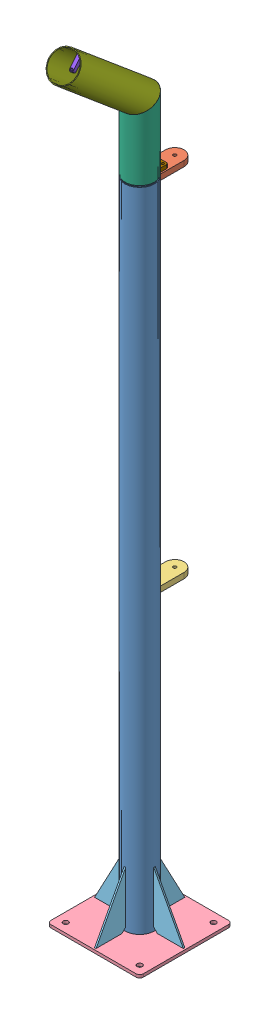
SolidWorks assembly FitLux_MecanoSoudure_Inox, configuration Default. Lengths in mm.
Overall size (250 2146.68 356.51).
14 component instances, 9 part files, 3 mates.
Components (placement in the parent):
- Ftx_Support-1: Ftx_Support [Défaut] at (-50.0643 -483.2351 108.1725) size (250 1758 250)
  - Tube_80x2x1750-1: Tube_80x2x1750 [Défaut] at (-29.6678 -485.0572 0) size (80 1750 80)
  - Ftx_BrideStatorSup-1: Ftx_BrideStatorSup [Défaut] at (-29.6678 1264.9428 0) x (-1 0 0) z (0 0 1) size (50 15 88.78)
  - Ftx_BrideStatorInf-1: Ftx_BrideStatorInf [Défaut] at (-29.6678 284.9428 0) size (50 15 88.78)
  - Ftx_Platine-1: Ftx_Platine [Défaut] at (-154.6678 -493.0572 125) size (250 8 250)
  - Ftx_Renfort-2: Ftx_Renfort [Défaut] at (-149.6678 -485.0572 0) size (80 150 4)
  - Ftx_Renfort-3: Ftx_Renfort [Défaut] at (-29.6678 -485.0572 120) x (0 0 -1) z (1 0 0) size (80 150 4)
  - Ftx_Renfort-4: Ftx_Renfort [Défaut] at (90.3322 -485.0572 0) x (-1 0 0) z (0 0 -1) size (80 150 4)
  - Ftx_Renfort-5: Ftx_Renfort [Défaut] at (-29.6678 -485.0572 -120) x (0 0 1) z (-1 0 0) size (80 150 4)
- Ftx_SupportEclairage-1: Ftx_SupportEclairage [Défaut] at (-79.7321 876.9485 65.011) x (0 0 -1) z (1 0 0) size (284.01 394.68 80)
  - Ftx_TubeEclairage_2-1: Ftx_TubeEclairage_2 [Défaut] at (-43.1615 -91.2409 0) size (80 210 80)
  - Ftx_TubeEclairage_1-1: Ftx_TubeEclairage_1 [Défaut] at (-248.9611 262.7932 0) x (0.642788 0.766044 0) z (0 0 -1) size (80 287.3 80)
  - Ftx_BrideEclairage-1: Ftx_BrideEclairage [Défaut] at (-219.8514 238.3672 0) x (-0.642788 -0.766044 0) z (0 0 -1) size (43 10 10)
  - Ftx_BrideSupportEclairage-1: Ftx_BrideSupportEclairage [Défaut] at (-43.1615 -91.2409 0) x (0 0 1) z (-1 0 0) size (50 10 21.28)
Mates (geometry in assembly coordinates):
- Coaxiale5: concentric aligned: cylinder of Ftx_Support-1/Ftx_BrideStatorSup-1 through (-62.2321 781.7076 63.1725) axis (0 1 0) radius 2.5; cylinder of Ftx_SupportEclairage-1/Ftx_BrideSupportEclairage-1 through (-62.2321 785.7076 63.1725) axis (0 1 0) radius 3.25
- Coaxiale6: concentric aligned: cylinder of Ftx_Support-1/Tube_80x2x1750-1 through (-79.7321 781.7076 108.1725) axis (0 -1 0) radius 38; cylinder of Ftx_SupportEclairage-1/Ftx_TubeEclairage_2-1 through (-79.7321 1085.7076 108.1725) axis (0 -1 0) radius 38
- Distance1: distance = 4 mm anti-aligned: plane of Ftx_SupportEclairage-1/Ftx_TubeEclairage_2-1 through (-79.7321 785.7076 108.1725) normal (0 -1 0); plane of Ftx_Support-1/Tube_80x2x1750-1 through (-79.7321 781.7076 108.1725) normal (0 1 0)
